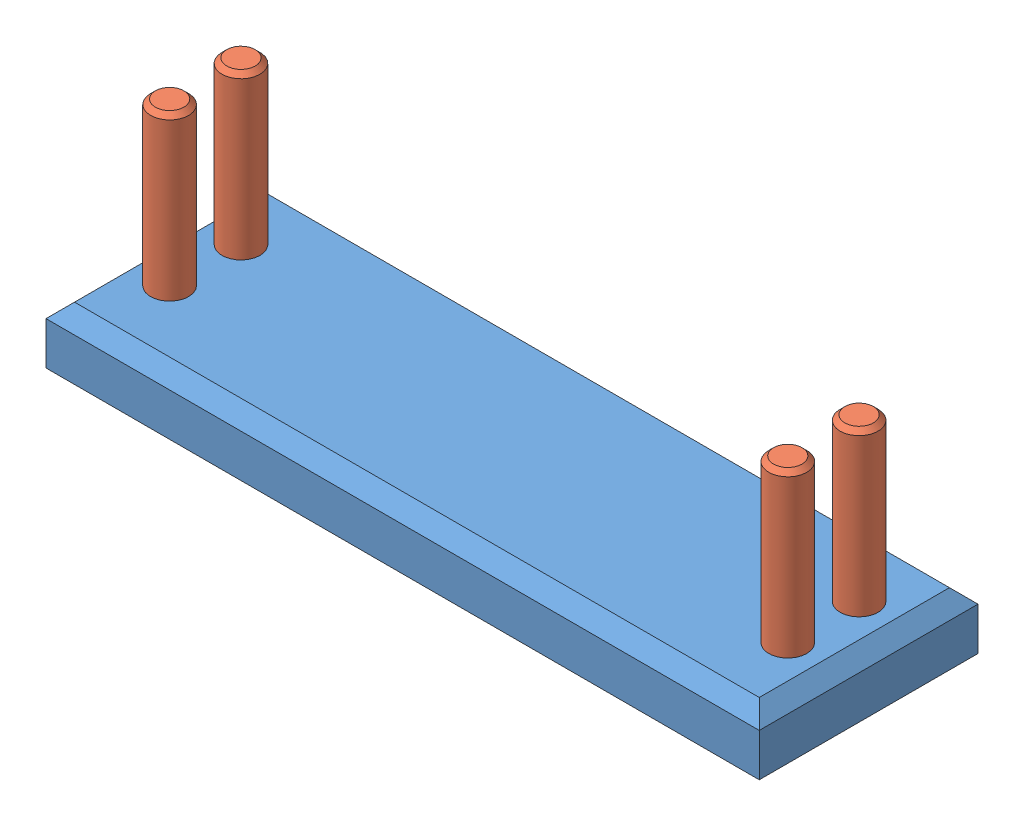
SolidWorks assembly Assem1, configuration Default. Lengths in mm.
Overall size (3810 1219.2 1168.4).
5 component instances, 2 part files, 4 mates.
Components (placement in the parent):
- picture_holder_base-1: picture_holder_base [Default] at (160.2851 -254.0539 -15.5181) size (3810 304.8 1168.4)
- picture_holder_pin-1: picture_holder_pin [Default] at (-1490.7149 914.3461 -218.7181) x (0.991946 0 0.126658) z (0.126658 0 -0.991946) size (203.2 1219.2 203.2)
- picture_holder_pin-2: picture_holder_pin [Default] at (-1490.7149 914.3461 162.2819) x (0.856226 0 0.516601) z (0.516601 0 -0.856226) size (203.2 1219.2 203.2)
- picture_holder_pin-3: picture_holder_pin [Default] at (1811.2851 914.3461 -218.7181) x (0.753212 0 0.657778) z (0.657778 0 -0.753212) size (203.2 1219.2 203.2)
- picture_holder_pin-4: picture_holder_pin [Default] at (1811.2851 914.3461 162.2819) x (0.663345 0 0.748314) z (0.748314 0 -0.663345) size (203.2 1219.2 203.2)
Mates (geometry in assembly coordinates):
- Coincident1: coincident anti-aligned: circle of picture_holder_base-1; circle of picture_holder_pin-1
- Coincident2: coincident anti-aligned: circle of picture_holder_base-1; circle of picture_holder_pin-2
- Coincident3: coincident anti-aligned: circle of picture_holder_base-1; circle of picture_holder_pin-3
- Coincident4: coincident anti-aligned: circle of picture_holder_base-1; circle of picture_holder_pin-4
